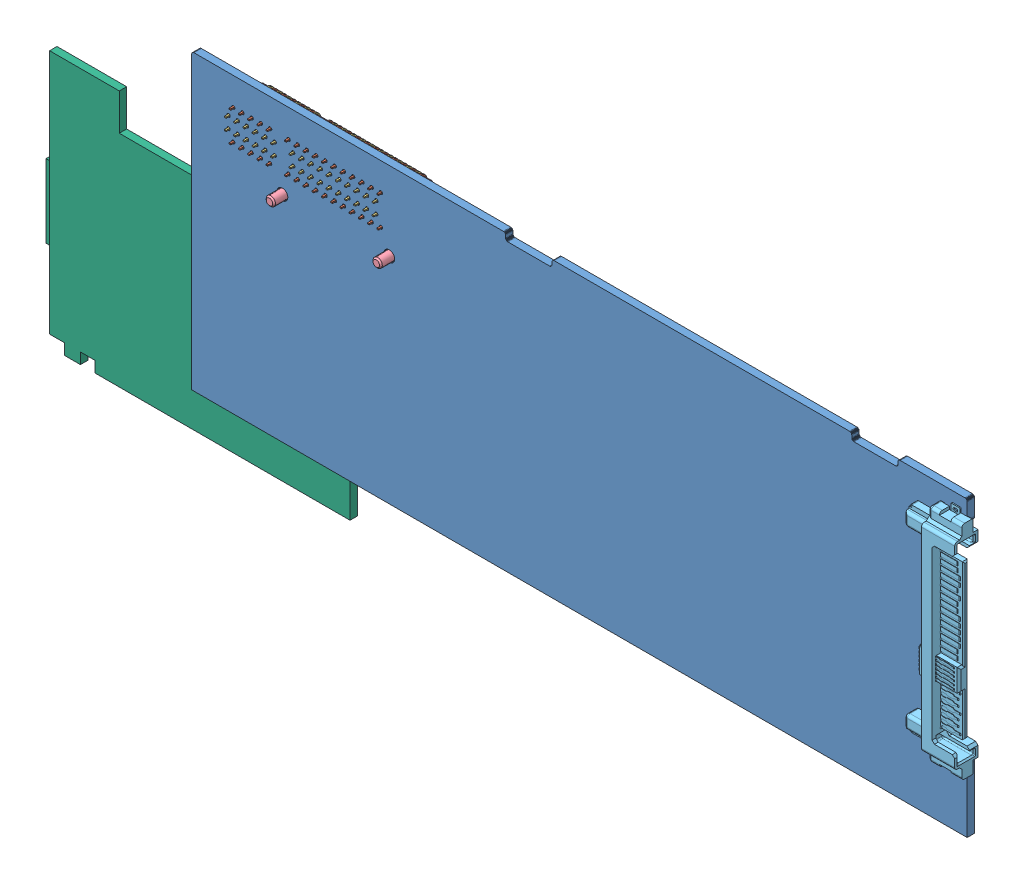
SolidWorks assembly K2v2, configuration Default. Lengths in mm.
Overall size (209.3 77.43 25.7).
9 component instances, 6 part files, 9 mates.
Components (placement in the parent):
- u2CEM.step-1: u2CEM.step [Default] at origin size (168 63.5 1.6)
  - u2CEM PCB.step-1: u2CEM PCB.step [Default] at origin size (168 63.5 1.6)
- PCIE-064-02-X-D-RA-1: PCIE-064-02-X-D-RA [Default] at (236.4945 -103.501 -5.8) x (-1 0 0) z (0 0 1) size (39 18.85 13.86)
  - PCIE-064-02-X-D-RA.step-1: PCIE-064-02-X-D-RA.step [Default] at origin size (39 18.85 13.86)
    - PCIE-064-02-F-D-RA_pins2.step-1: PCIE-064-02-F-D-RA_pins2.step [Default] at (6.9945 0 0) size (34 17.93 10.46)
    - PCIE-064-02-F-D-RA_pins1.step-1: PCIE-064-02-F-D-RA_pins1.step [Default] at (6.9945 0 0) size (34 16.93 10.47)
    - PCIE-064-02-F-D-RA_body.step-1: PCIE-064-02-F-D-RA_body.step [Default] at origin size (39 18.85 13.86)
- 3d_model_psas4m213002xxx-1: 3d_model_psas4m213002xxx [Default] at (374.1 -116.95 3.6) x (0 1 0) z (0 0 -1) size (49.45 12.58 5.15)
- CEM_NIC-1: CEM_NIC [Default] at (239.7 -107.1 -6.6) x (-1 0 0) z (0 0 1) size (67.47 60.32 15.1)
Mates (geometry in assembly coordinates):
- Parallel1: parallel aligned: plane of u2CEM.step-1/u2CEM PCB.step-1 through (212 -153.5 0) normal (-1 0 0); plane of PCIE-064-02-X-D-RA-1/PCIE-064-02-X-D-RA.step-1/PCIE-064-02-F-D-RA_body.step-1 through (217 -113.85 0) normal (-1 0 0)
- Coincident1: coincident anti-aligned: plane of u2CEM.step-1/u2CEM PCB.step-1 through (298.5644 -121.4016 0) normal (0 0 -1); plane of PCIE-064-02-X-D-RA-1/PCIE-064-02-X-D-RA.step-1/PCIE-064-02-F-D-RA_body.step-1 through (256 -113.85 0) normal (0 0 1)
- Concentric1: concentric anti-aligned: cylinder of u2CEM.step-1/u2CEM PCB.step-1 through (231.65 -107 -0.8) axis (0 0 1) radius 1.175; cylinder of PCIE-064-02-X-D-RA-1/PCIE-064-02-X-D-RA.step-1/PCIE-064-02-F-D-RA_body.step-1 through (231.65 -107 -0.2949) axis (0 0 -1) radius 1
- Concentric2: concentric anti-aligned: cylinder of u2CEM.step-1/u2CEM PCB.step-1 through (371.2 -97.48 -0.8) axis (0 0 1) radius 0.825; cylinder of 3d_model_psas4m213002xxx-1 through (371.2 -97.48 2.0115) axis (0 0 -1) radius 0.7
- Coincident2: coincident anti-aligned: plane of u2CEM.step-1/u2CEM PCB.step-1 through (298.5644 -121.4016 1.6) normal (0 0 1); plane of 3d_model_psas4m213002xxx-1 through (377.7 -92.95 1.6) normal (0 0 -1)
- Parallel2: parallel aligned: plane of u2CEM.step-1/u2CEM PCB.step-1 through (376 -100 0) normal (1 0 0); plane of 3d_model_psas4m213002xxx-1 through (376.4 -116.95 3.6) normal (1 0 0)
- Coincident3: coincident: plane of PCIE-064-02-X-D-RA-1/PCIE-064-02-X-D-RA.step-1/PCIE-064-02-F-D-RA_body.step-1 through (230.6 -114.5546 -6.7) normal (-1 0 0); plane of CEM_NIC-1 through (230.6 -107.1 -3.722) normal (1 0 0)
- Coincident4: coincident: plane of PCIE-064-02-X-D-RA-1/PCIE-064-02-X-D-RA.step-1/PCIE-064-02-F-D-RA_body.step-1 through (236.4945 -114.55 -5.8) normal (0 -1 0); line of CEM_NIC-1 through (232.5 -114.55 -3.722) axis (0 0 -1)
- Distance1: distance = 0.1 mm anti-aligned: plane of CEM_NIC-1 through (217.65 -118.05 -6.6) normal (0 0 -1); plane of PCIE-064-02-X-D-RA-1/PCIE-064-02-X-D-RA.step-1/PCIE-064-02-F-D-RA_body.step-1 through (218.95 -114.5546 -6.7) normal (0 0 1)
